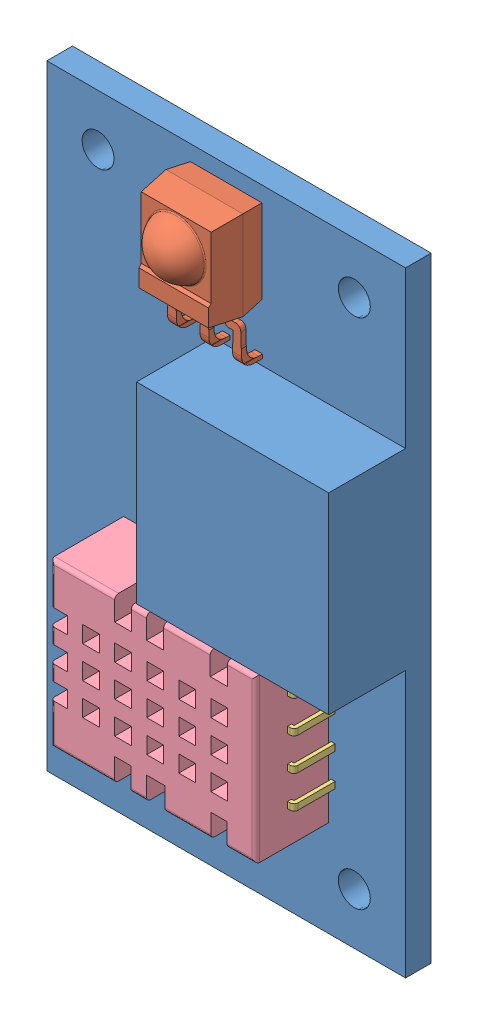
SolidWorks assembly PLACAIRDHT, configuration Predeterminado. Lengths in mm.
Overall size (28 48 10.4).
5 component instances, 4 part files, 6 mates.
Components (placement in the parent):
- PCB-1: PCB [Predeterminado] at (-0.1873 5.95 -1) size (28 48 8)
- IRREC-1: IRREC [Predeterminado] at (-0.1873 25.475 2.7) x (1 0 0) z (0 -1 0) size (6 8.11 10.7)
- DHT11-1: DHT11 [Predeterminado] at (-0.1873 -4.2 1) x (-1 0 0) z (0 0 1) size (16.5 12.7 10.1)
  - Array002-1: Array002 [Predeterminado] at origin size (0.5 8.12 7.6)
  - Cut-1: Cut [Predeterminado] at origin size (16 12.7 5.7)
Mates (geometry in assembly coordinates):
- Coincidente1: coincident anti-aligned: plane of PCB-1 through (-0.1873 5.95 1) normal (0 0 1); plane of DHT11-1/Cut-1 through (-0.1873 -4.2 1) normal (0 0 -1)
- Distancia1: distance = 7.5 mm aligned: plane of DHT11-1/Cut-1 through (7.8127 -10.55 1) normal (0 -1 0); plane of PCB-1 through (-14.1873 -18.05 1) normal (0 -1 0)
- Ancho1: width anti-aligned: plane of DHT11-1/Cut-1 through (7.8127 2.15 1) normal (1 0 0); plane of DHT11-1/Cut-1 through (-8.1873 -10.55 1) normal (-1 0 0); plane of PCB-1 through (-14.1873 -18.05 1) normal (-1 0 0); plane of PCB-1 through (13.8127 -18.05 1) normal (1 0 0)
- Ancho2: width aligned: plane of IRREC-1 through (-3.1858 28.8897 2.6878) normal (-0.992546 0 -0.121869); plane of IRREC-1 through (2.6148 28.8897 1.0878) normal (0.992546 0 -0.121869); plane of PCB-1 through (13.8127 -18.05 1) normal (1 0 0); plane of PCB-1 through (-14.1873 -18.05 1) normal (-1 0 0)
- Coincidente3: coincident anti-aligned: plane of PCB-1 through (-0.1873 5.95 1) normal (0 0 1); plane of IRREC-1 through (-2.8901 22.2972 1) normal (0 0 -1)
- Distancia3: distance = 1 mm: line of IRREC-1 through (-3.1873 28.95 2.7) axis (1 0 0); plane of PCB-1 through (-14.1873 29.95 1) normal (0 1 0)
